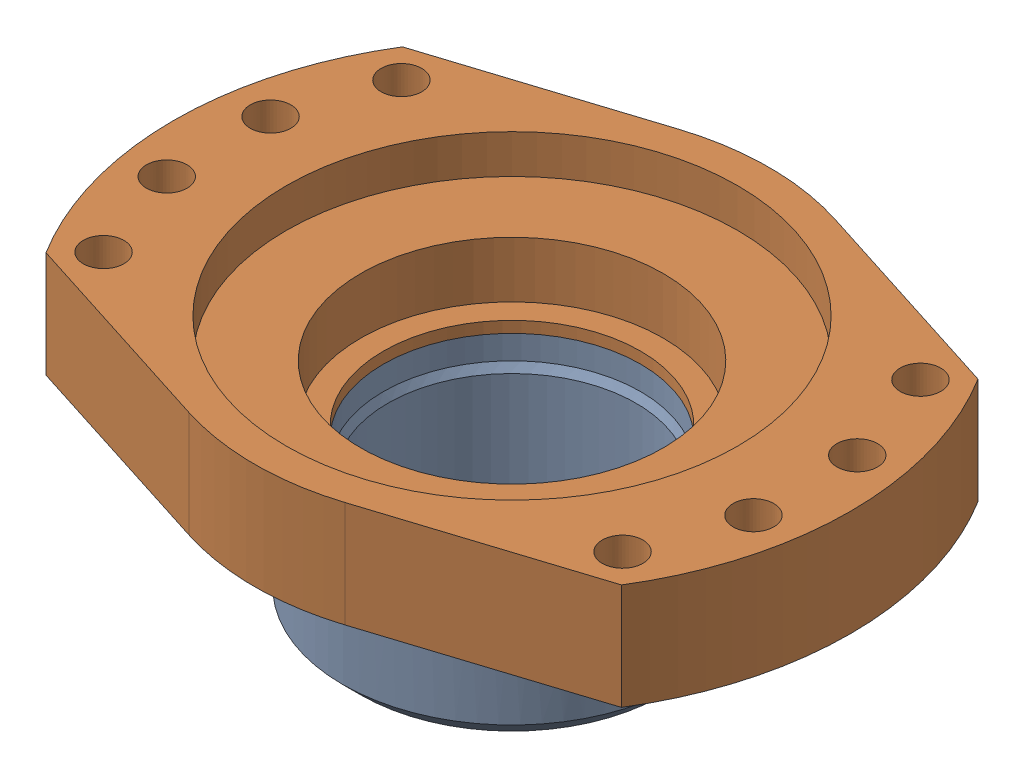
SolidWorks assembly g1_3_1_1_1_1_1, configuration 默认. Lengths in mm.
Overall size (300 112 228).
2 component instances, 2 part files, 0 mates.
Components (placement in the parent):
- g1_3_1_1_1_1-2_af0_1-1: g1_3_1_1_1_1-2_af0_1 [默认] at (0 50 0) size (150 65 150)
- g1_3_1_1_1_1-3_af0_1-1: g1_3_1_1_1_1-3_af0_1 [默认] at (0 140 0) size (300 47 228)
